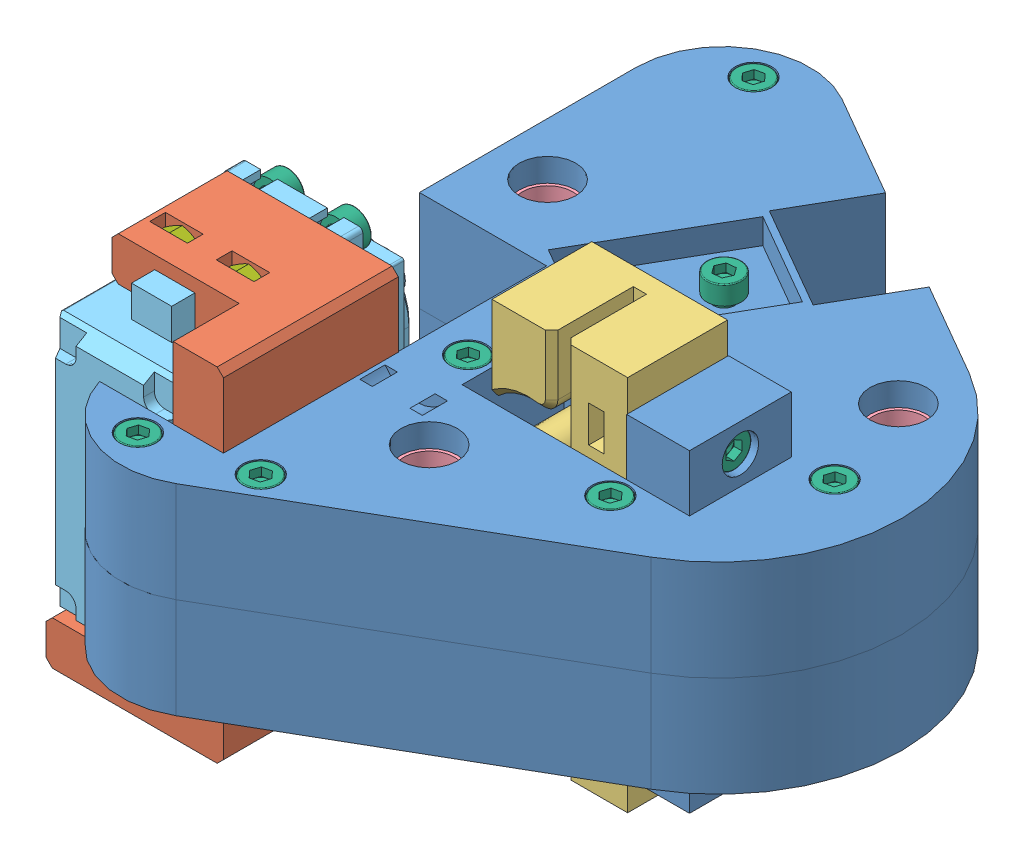
SolidWorks assembly PBewegAssembly, configuration Default. Lengths in mm.
Overall size (91.25 64 109.71).
35 component instances, 7 part files, 82 mates.
Components (placement in the parent):
- PBeweglich-1: PBeweglich [top] at origin size (83.34 25 109.71)
- PServoHolder-1: PServoHolder [Default] at (-25.65 0.0661 17.2) size (34.15 54.65 27.84)
- PRiemenklemme-1: PRiemenklemme [Default] at (7.3 0 3.45) x (1 0 0) z (0 -1 0) size (21.6 15.9 60)
- _LinearBallBearing-1: _LinearBallBearing [Standard] at (29.25 0.4 -15.5) x (1 0 0) z (0 -1 0) size (15 15 24)
- _LinearBallBearing-2: _LinearBallBearing [Standard] at (-29.6 0.4 -18.5) x (1 0 0) z (0 -1 0) size (15 15 24)
- _LinearBallBearing-3: _LinearBallBearing [Standard] at (-2.4435 0.4 27.5) x (1 0 0) z (0 -1 0) size (15 15 24)
- _Analogservo_1501MG-1: _Analogservo_1501MG [Default] at (-35.78 0.0661 45) x (0 -1 0) z (0 0 -1) size (54.65 20.25 44.05)
- PBeweglich-2: PBeweglich [bottom] at origin size (83.34 34 109.71)
- socket head cap screw_iso-2: socket head cap screw_iso [ISO 4762 M3 x 30 - 18N] at (-3 16 -20) x (0 -1 0) z (0.106738 0 0.994287) size (33 5.5 5.5)
- socket head cap screw_iso-4: socket head cap screw_iso [ISO 4762 M3 x 12 - 12N] at (27.1 20.5 8.5) x (-1 0 0) z (0 0 1) size (15 5.5 5.5)
- hex nut style 1 gradeab_iso-1: hex nut style 1 gradeab_iso [ISO - 4032 - M3 - D - N] at (11.9 20.5 8.5) x (0 -0.5 0.866025) z (-1 0 0) size (5.5 6.35 2.4)
- hex nut style 1 gradeab_iso-2: hex nut style 1 gradeab_iso [ISO - 4032 - M3 - D - N] at (14.3 -20.5 8.5) x (0 0.5 -0.866025) z (1 0 0) size (5.5 6.35 2.4)
- socket head cap screw_iso-5: socket head cap screw_iso [ISO 4762 M3 x 12 - 12N] at (27.1 -20.5 8.5) x (-1 0 0) z (0 0.109036 -0.994038) size (15 5.5 5.5)
- socket head cap screw_iso-6: socket head cap screw_iso [ISO 4762 M3 x 30 - 18N] at (19 16 20.1) x (0 -1 0) z (0.214721 0 0.976675) size (33 5.5 5.5)
- socket head cap screw_iso-7: socket head cap screw_iso [ISO 4762 M3 x 30 - 18N] at (-11.75 16 45) x (0 -1 0) z (0.214721 0 0.976675) size (33 5.5 5.5)
- socket head cap screw_iso-8: socket head cap screw_iso [ISO 4762 M3 x 30 - 18N] at (-11.75 16 12) x (0 -1 0) z (0.214721 0 0.976675) size (33 5.5 5.5)
- socket head cap screw_iso-9: socket head cap screw_iso [ISO 4762 M3 x 30 - 18N] at (34.6 16 0) x (0 -1 0) z (0.214721 0 0.976675) size (33 5.5 5.5)
- socket head cap screw_iso-10: socket head cap screw_iso [ISO 4762 M3 x 30 - 18N] at (-27.3127 16 -49) x (0 -1 0) z (0.214721 0 0.976675) size (33 5.5 5.5)
- socket head cap screw_iso-11: socket head cap screw_iso [ISO 4762 M3 x 30 - 18N] at (-27.3127 16 49) x (0 -1 0) z (0.214721 0 0.976675) size (33 5.5 5.5)
- hex nut style 1 gradeab_iso-4: hex nut style 1 gradeab_iso [ISO - 4032 - M3 - D - N] at (-11.75 -13.6 45) x (1 0 0) z (0 1 0) size (5.5 6.35 2.4)
- hex nut style 1 gradeab_iso-5: hex nut style 1 gradeab_iso [ISO - 4032 - M3 - D - N] at (-27.3127 -13.6 49) x (0.866025 0 0.5) z (0 1 0) size (5.5 6.35 2.4)
- hex nut style 1 gradeab_iso-6: hex nut style 1 gradeab_iso [ISO - 4032 - M3 - D - N] at (34.6 -13.6 0) x (1 0 0) z (0 1 0) size (5.5 6.35 2.4)
- hex nut style 1 gradeab_iso-7: hex nut style 1 gradeab_iso [ISO - 4032 - M3 - D - N] at (-27.3127 -13.6 -49) x (1 0 0) z (0 1 0) size (5.5 6.35 2.4)
- hex nut style 1 gradeab_iso-9: hex nut style 1 gradeab_iso [ISO - 4032 - M3 - D - N] at (-3 -13.6 -20) x (1 0 0) z (0 1 0) size (5.5 6.35 2.4)
- hex nut style 1 gradeab_iso-10: hex nut style 1 gradeab_iso [ISO - 4032 - M3 - D - N] at (-11.75 -13.6 12) x (1 0 0) z (0 1 0) size (5.5 6.35 2.4)
- hex nut style 1 gradeab_iso-11: hex nut style 1 gradeab_iso [ISO - 4032 - M3 - D - N] at (19 -13.6 20.1) x (1 0 0) z (0 1 0) size (5.5 6.35 2.4)
- socket head cap screw_iso-14: socket head cap screw_iso [ISO 4762 M3 x 16 - 16N] at (-41.08 24.0711 11.35) x (0 0 1) z (-0.923728 -0.383049 0) size (19 5.5 5.5)
- socket head cap screw_iso-15: socket head cap screw_iso [ISO 4762 M3 x 16 - 16N] at (-30.48 24.0711 11.35) x (0 0 1) z (-0.165915 -0.98614 0) size (19 5.5 5.5)
- socket head cap screw_iso-16: socket head cap screw_iso [ISO 4762 M3 x 16 - 16N] at (-30.48 -23.9389 11.35) x (0 0 1) z (-0.163472 0.986548 0) size (19 5.5 5.5)
- socket head cap screw_iso-17: socket head cap screw_iso [ISO 4762 M3 x 16 - 16N] at (-41.08 -23.9389 11.35) x (0 0 1) z (0.653973 0.756518 0) size (19 5.5 5.5)
- hex nut style 1 gradeab_iso-12: hex nut style 1 gradeab_iso [ISO - 4032 - M3 - D - N] at (-41.08 -23.9389 30.35) size (5.5 6.35 2.4)
- hex nut style 1 gradeab_iso-13: hex nut style 1 gradeab_iso [ISO - 4032 - M3 - D - N] at (-30.48 -23.9389 30.35) x (0.5 0.866025 0) z (0 0 1) size (5.5 6.35 2.4)
- hex nut style 1 gradeab_iso-14: hex nut style 1 gradeab_iso [ISO - 4032 - M3 - D - N] at (-30.58 -24.005 30.35) x (0.5 0.866025 0) z (0 0 1) size (5.5 6.35 2.4)
- hex nut style 1 gradeab_iso-15: hex nut style 1 gradeab_iso [ISO - 4032 - M3 - D - N] at (-30.48 24.0711 30.35) x (0.5 -0.866025 0) z (0 0 1) size (5.5 6.35 2.4)
- hex nut style 1 gradeab_iso-16: hex nut style 1 gradeab_iso [ISO - 4032 - M3 - D - N] at (-41.08 24.0711 30.35) x (-0.5 0.866025 0) z (0 0 1) size (5.5 6.35 2.4)
Mates (geometry in assembly coordinates):
- Coincident3: coincident anti-aligned: plane of PBeweglich-1 through (-11.75 0 16.9) normal (-1 0 0); plane of PServoHolder-1 through (-11.75 0.0661 45.04) normal (1 0 0)
- Concentric3: concentric aligned: cylinder of PBeweglich-1 through (-3 0 -20) axis (0 1 0) radius 1.7; cylinder of socket head cap screw_iso-2 through (-3 47.75 -20) axis (0 1 0) radius 1.5
- Concentric4: concentric aligned: cylinder of PBeweglich-1 through (-38 20.5 8.5) axis (1 0 0) radius 1.75; cylinder of PRiemenklemme-1 through (-3.501 20.5 8.5) axis (1 0 0) radius 1.7
- Concentric6: concentric aligned: cylinder of PBeweglich-1 through (-38 20.5 8.5) axis (1 0 0) radius 1.75; cylinder of socket head cap screw_iso-4 through (58.85 20.5 8.5) axis (1 0 0) radius 1.5
- Coincident8: coincident anti-aligned: plane of PBeweglich-1 through (24.1 20.5 8.5) normal (1 0 0); plane of socket head cap screw_iso-4 through (24.1 17.75 8.5) normal (-1 0 0)
- Coincident13: coincident anti-aligned: plane of PBeweglich-1 through (29.25 12 -15.5) normal (0 -1 0); plane of _LinearBallBearing-1 through (29.25 12 -9) normal (0 1 0)
- Concentric9: concentric anti-aligned: cylinder of PBeweglich-1 through (29.25 12 -15.5) axis (0 -1 0) radius 7.65; cylinder of _LinearBallBearing-1 through (29.25 0.4 -15.5) axis (0 1 0) radius 7.5
- Coincident15: coincident anti-aligned: plane of PBeweglich-1 through (-29.6 12 -18.5) normal (0 -1 0); plane of _LinearBallBearing-2 through (-29.6 12 -12) normal (0 1 0)
- Concentric10: concentric anti-aligned: cylinder of PBeweglich-1 through (-29.6 12 -18.5) axis (0 -1 0) radius 7.65; cylinder of _LinearBallBearing-2 through (-29.6 0.4 -18.5) axis (0 1 0) radius 7.5
- Coincident16: coincident anti-aligned: plane of PBeweglich-1 through (-2.4435 12 27.5) normal (0 -1 0); plane of _LinearBallBearing-3 through (-2.4435 12 34) normal (0 1 0)
- Concentric11: concentric anti-aligned: cylinder of PBeweglich-1 through (-2.4435 12 27.5) axis (0 -1 0) radius 7.65; cylinder of _LinearBallBearing-3 through (-2.4435 0.4 27.5) axis (0 1 0) radius 7.5
- Concentric12: concentric anti-aligned: cylinder of PServoHolder-1 through (-30.48 24.0711 30.35) axis (0 0 -1) radius 1.7; cylinder of _Analogservo_1501MG-1 through (-30.48 24.0711 14.35) axis (0 0 1) radius 2.5
- Concentric13: concentric anti-aligned: cylinder of PServoHolder-1 through (-41.08 24.0711 30.35) axis (0 0 -1) radius 1.7; cylinder of _Analogservo_1501MG-1 through (-41.08 24.0711 14.35) axis (0 0 1) radius 2.5
- Coincident18: coincident anti-aligned: plane of PServoHolder-1 through (-25.65 0.0661 17.2) normal (0 0 -1); plane of _Analogservo_1501MG-1 through (-35.78 0.0661 17.2) normal (0 0 1)
- Concentric15: concentric anti-aligned: cylinder of socket head cap screw_iso-4 through (58.85 20.5 8.5) axis (1 0 0) radius 1.5; cylinder of hex nut style 1 gradeab_iso-1 through (14.3 20.5 8.5) axis (-1 0 0) radius 1.25
- Coincident19: coincident anti-aligned: plane of PRiemenklemme-1 through (14.3 0 16.45) normal (-1 0 0); plane of hex nut style 1 gradeab_iso-1 through (14.3 23.25 10.0877) normal (1 0 0)
- Parallel1: parallel aligned: plane of PRiemenklemme-1 through (7.3 23.4 16.45) normal (0 -1 0); plane of hex nut style 1 gradeab_iso-1 through (14.3 17.75 6.9123) normal (0 -1 0)
- Coincident22: coincident anti-aligned: plane of PRiemenklemme-1 through (14.3 0 16.45) normal (-1 0 0); plane of hex nut style 1 gradeab_iso-2 through (14.3 -17.75 10.0877) normal (1 0 0)
- Concentric18: concentric aligned: cylinder of hex nut style 1 gradeab_iso-2 through (11.9 -20.5 8.5) axis (1 0 0) radius 1.25; cylinder of socket head cap screw_iso-5 through (58.85 -20.5 8.5) axis (1 0 0) radius 1.5
- Parallel2: parallel anti-aligned: plane of PRiemenklemme-1 through (7.3 -23.4 16.45) normal (0 1 0); plane of hex nut style 1 gradeab_iso-2 through (11.9 -23.25 10.0877) normal (0 -1 0)
- Concentric19: concentric aligned: cylinder of socket head cap screw_iso-5 through (58.85 -20.5 8.5) axis (1 0 0) radius 1.5; cylinder of PBeweglich-2 through (-38 -20.5 8.5) axis (1 0 0) radius 1.75
- Coincident24: coincident anti-aligned: plane of socket head cap screw_iso-5 through (24.1 -17.7664 8.7999) normal (-1 0 0); plane of PBeweglich-2 through (24.1 -20.5 8.5) normal (1 0 0)
- Coincident25: coincident anti-aligned: plane of PRiemenklemme-1 through (14.3 0 16.45) normal (-1 0 0); plane of hex nut style 1 gradeab_iso-2 through (14.3 -17.75 10.0877) normal (1 0 0)
- Coincident26: coincident anti-aligned: plane of PBeweglich-1 through (0 0 0) normal (0 -1 0); plane of PBeweglich-2 through (0 0 0) normal (0 1 0)
- Concentric20: concentric anti-aligned: cylinder of PBeweglich-1 through (-11.75 0 45) axis (0 1 0) radius 1.7; cylinder of PBeweglich-2 through (-11.75 0 45) axis (0 -1 0) radius 1.7
- Concentric21: concentric anti-aligned: cylinder of PBeweglich-1 through (-27.3127 0 -49) axis (0 1 0) radius 1.7; cylinder of PBeweglich-2 through (-27.3127 0 -49) axis (0 -1 0) radius 1.7
- Concentric22: concentric aligned: cylinder of PBeweglich-1 through (34.6 0 0) axis (0 1 0) radius 1.7; cylinder of socket head cap screw_iso-9 through (34.6 47.75 0) axis (0 1 0) radius 1.5
- Concentric23: concentric aligned: cylinder of PBeweglich-1 through (19 0 20.1) axis (0 1 0) radius 1.7; cylinder of socket head cap screw_iso-6 through (19 47.75 20.1) axis (0 1 0) radius 1.5
- Coincident27: coincident: circle of PBeweglich-1; cylinder of socket head cap screw_iso-7 through (-11.75 47.75 45) axis (0 1 0) radius 1.5
- Concentric24: concentric aligned: cylinder of PBeweglich-1 through (-11.75 0 12) axis (0 1 0) radius 1.7; cylinder of socket head cap screw_iso-8 through (-11.75 47.75 12) axis (0 1 0) radius 1.5
- Concentric25: concentric aligned: cylinder of PBeweglich-1 through (-27.3127 0 -49) axis (0 1 0) radius 1.7; cylinder of socket head cap screw_iso-10 through (-27.3127 47.75 -49) axis (0 1 0) radius 1.5
- Concentric26: concentric aligned: cylinder of PBeweglich-1 through (-27.3127 0 49) axis (0 1 0) radius 1.7; cylinder of socket head cap screw_iso-11 through (-27.3127 47.75 49) axis (0 1 0) radius 1.5
- Coincident28: coincident anti-aligned: plane of PBeweglich-1 through (34.6 13 0) normal (0 1 0); plane of socket head cap screw_iso-9 through (37.2859 13 -0.5905) normal (0 -1 0)
- Coincident29: coincident anti-aligned: plane of PBeweglich-1 through (-27.3127 13 -49) normal (0 1 0); plane of socket head cap screw_iso-10 through (-24.6269 13 -49.5905) normal (0 -1 0)
- Coincident30: coincident anti-aligned: circle of PBeweglich-1; plane of socket head cap screw_iso-8 through (-9.0641 13 11.4095) normal (0 -1 0)
- Coincident31: coincident anti-aligned: plane of PBeweglich-1 through (19 13 20.1) normal (0 1 0); plane of socket head cap screw_iso-6 through (21.6859 13 19.5095) normal (0 -1 0)
- Coincident32: coincident aligned: plane of PBeweglich-1 through (-11.75 13 45) normal (0 1 0); circle of socket head cap screw_iso-7
- Coincident33: coincident anti-aligned: plane of PBeweglich-1 through (-27.3127 13 49) normal (0 1 0); plane of socket head cap screw_iso-11 through (-24.6269 13 48.4095) normal (0 -1 0)
- Concentric27: concentric anti-aligned: cylinder of socket head cap screw_iso-7 through (-11.75 47.75 45) axis (0 1 0) radius 1.5; circle of hex nut style 1 gradeab_iso-4
- Concentric29: concentric aligned: cylinder of socket head cap screw_iso-11 through (-27.3127 47.75 49) axis (0 1 0) radius 1.5; cylinder of hex nut style 1 gradeab_iso-5 through (-27.3127 -16 49) axis (0 1 0) radius 1.25
- Coincident34: coincident aligned: cylinder of socket head cap screw_iso-6 through (19 47.75 20.1) axis (0 1 0) radius 1.5; circle of hex nut style 1 gradeab_iso-11
- Concentric30: concentric aligned: cylinder of socket head cap screw_iso-8 through (-11.75 47.75 12) axis (0 1 0) radius 1.5; cylinder of hex nut style 1 gradeab_iso-10 through (-11.75 -16 12) axis (0 1 0) radius 1.25
- Concentric31: concentric aligned: cylinder of socket head cap screw_iso-2 through (-3 47.75 -20) axis (0 1 0) radius 1.5; cylinder of hex nut style 1 gradeab_iso-9 through (-3 -16 -20) axis (0 1 0) radius 1.25
- Concentric32: concentric aligned: cylinder of socket head cap screw_iso-10 through (-27.3127 47.75 -49) axis (0 1 0) radius 1.5; cylinder of hex nut style 1 gradeab_iso-7 through (-27.3127 -16 -49) axis (0 1 0) radius 1.25
- Concentric33: concentric aligned: cylinder of socket head cap screw_iso-9 through (34.6 47.75 0) axis (0 1 0) radius 1.5; cylinder of hex nut style 1 gradeab_iso-6 through (34.6 -16 0) axis (0 1 0) radius 1.25
- Parallel3: parallel: line of PBeweglich-2 through (22 -16 21.8321) axis (0 0 -1); plane of hex nut style 1 gradeab_iso-11 through (21.75 -16 18.5123) normal (1 0 0)
- Parallel4: parallel: line of PBeweglich-2 through (-8.75 -16 46.7321) axis (0 0 -1); plane of hex nut style 1 gradeab_iso-4 through (-9 -16 43.4123) normal (1 0 0)
- Parallel5: parallel: line of PBeweglich-2 through (-25.5807 -16 52) axis (0.5 0 -0.866025); plane of hex nut style 1 gradeab_iso-5 through (-24.1373 -16 49) normal (0.866025 0 0.5)
- Parallel6: parallel: line of PBeweglich-2 through (-8.75 -16 13.7321) axis (0 0 -1); plane of hex nut style 1 gradeab_iso-10 through (-9 -16 10.4123) normal (1 0 0)
- Parallel7: parallel: line of PBeweglich-2 through (0 -16 -18.2679) axis (0 0 -1); plane of hex nut style 1 gradeab_iso-9 through (-0.25 -16 -21.5877) normal (1 0 0)
- Parallel8: parallel: line of PBeweglich-2 through (37.6 -16 1.7321) axis (0 0 -1); plane of hex nut style 1 gradeab_iso-6 through (37.35 -16 -1.5877) normal (1 0 0)
- Parallel9: parallel: line of PBeweglich-2 through (-24.3127 -16 -47.2679) axis (0 0 -1); plane of hex nut style 1 gradeab_iso-7 through (-24.5627 -16 -50.5877) normal (1 0 0)
- Coincident43: coincident anti-aligned: plane of PBeweglich-2 through (0 -13.6 0) normal (0 -1 0); plane of hex nut style 1 gradeab_iso-11 through (19 -13.6 16.9246) normal (0 1 0)
- Coincident44: coincident anti-aligned: plane of PBeweglich-2 through (0 -13.6 0) normal (0 -1 0); plane of hex nut style 1 gradeab_iso-10 through (-11.75 -13.6 8.8246) normal (0 1 0)
- Coincident45: coincident anti-aligned: plane of PBeweglich-2 through (0 -13.6 0) normal (0 -1 0); plane of hex nut style 1 gradeab_iso-6 through (34.6 -13.6 -3.1754) normal (0 1 0)
- Coincident46: coincident anti-aligned: plane of PBeweglich-2 through (0 -13.6 0) normal (0 -1 0); plane of hex nut style 1 gradeab_iso-9 through (-3 -13.6 -23.1754) normal (0 1 0)
- Coincident47: coincident anti-aligned: plane of PBeweglich-2 through (0 -13.6 0) normal (0 -1 0); plane of hex nut style 1 gradeab_iso-7 through (-27.3127 -13.6 -52.1754) normal (0 1 0)
- Coincident48: coincident anti-aligned: plane of PBeweglich-2 through (0 -13.6 0) normal (0 -1 0); plane of hex nut style 1 gradeab_iso-4 through (-11.75 -13.6 41.8246) normal (0 1 0)
- Coincident49: coincident anti-aligned: plane of PBeweglich-2 through (0 -13.6 0) normal (0 -1 0); plane of hex nut style 1 gradeab_iso-5 through (-25.725 -13.6 46.25) normal (0 1 0)
- Coincident52: coincident anti-aligned: plane of _Analogservo_1501MG-1 through (-35.78 0.0661 45) normal (0 0 1); plane of PBeweglich-2 through (0 -12 45) normal (0 0 -1)
- Concentric39: concentric aligned: cylinder of PServoHolder-1 through (-41.08 24.0711 30.35) axis (0 0 -1) radius 1.7; cylinder of socket head cap screw_iso-14 through (-41.08 24.0711 -20.4) axis (0 0 -1) radius 1.5
- Coincident55: coincident anti-aligned: plane of _Analogservo_1501MG-1 through (-35.78 0.0661 14.35) normal (0 0 -1); plane of socket head cap screw_iso-14 through (-42.1334 26.6114 14.35) normal (0 0 1)
- Concentric40: concentric aligned: cylinder of PServoHolder-1 through (-30.48 24.0711 30.35) axis (0 0 -1) radius 1.7; cylinder of socket head cap screw_iso-15 through (-30.48 24.0711 -20.4) axis (0 0 -1) radius 1.5
- Coincident56: coincident aligned: plane of _Analogservo_1501MG-1 through (-35.78 0.0661 14.35) normal (0 0 -1); circle of socket head cap screw_iso-15
- Concentric41: concentric aligned: cylinder of PServoHolder-1 through (-30.48 -23.9389 30.35) axis (0 0 -1) radius 1.7; cylinder of socket head cap screw_iso-16 through (-30.48 -23.9389 -20.4) axis (0 0 -1) radius 1.5
- Concentric42: concentric aligned: cylinder of PServoHolder-1 through (-41.08 -23.9389 30.35) axis (0 0 -1) radius 1.7; cylinder of socket head cap screw_iso-17 through (-41.08 -23.9389 -20.4) axis (0 0 -1) radius 1.5
- Coincident57: coincident anti-aligned: plane of _Analogservo_1501MG-1 through (-35.78 0.0661 14.35) normal (0 0 -1); plane of socket head cap screw_iso-17 through (-38.9996 -25.7373 14.35) normal (0 0 1)
- Coincident58: coincident anti-aligned: plane of _Analogservo_1501MG-1 through (-35.78 0.0661 14.35) normal (0 0 -1); plane of socket head cap screw_iso-16 through (-27.767 -23.4894 14.35) normal (0 0 1)
- Concentric43: concentric anti-aligned: cylinder of socket head cap screw_iso-17 through (-41.08 -23.9389 -20.4) axis (0 0 -1) radius 1.5; cylinder of hex nut style 1 gradeab_iso-12 through (-41.08 -23.9389 27.95) axis (0 0 1) radius 1.25
- Parallel12: parallel anti-aligned: plane of PServoHolder-1 through (-38.08 -21.2589 27.85) normal (-1 0 0); plane of hex nut style 1 gradeab_iso-12 through (-38.33 -22.3512 27.95) normal (1 0 0)
- Coincident60: coincident anti-aligned: plane of PServoHolder-1 through (-41.08 -23.9389 30.35) normal (0 0 -1); plane of hex nut style 1 gradeab_iso-12 through (-41.08 -20.7635 30.35) normal (0 0 1)
- Concentric44: concentric anti-aligned: cylinder of socket head cap screw_iso-16 through (-30.48 -23.9389 -20.4) axis (0 0 -1) radius 1.5; cylinder of hex nut style 1 gradeab_iso-13 through (-30.48 -23.9389 27.95) axis (0 0 1) radius 1.25
- Parallel13: parallel anti-aligned: plane of PServoHolder-1 through (-27.48 -21.2589 27.85) normal (-1 0 0); plane of hex nut style 1 gradeab_iso-13 through (-27.73 -25.5266 27.95) normal (1 0 0)
- Coincident62: coincident anti-aligned: plane of PServoHolder-1 through (-30.48 -23.9389 30.35) normal (0 0 -1); plane of hex nut style 1 gradeab_iso-13 through (-33.23 -22.3512 30.35) normal (0 0 1)
- Coincident63: coincident anti-aligned: cylinder of socket head cap screw_iso-14 through (-41.08 24.0711 -20.4) axis (0 0 -1) radius 1.5; circle of hex nut style 1 gradeab_iso-16
- Concentric45: concentric aligned: cylinder of socket head cap screw_iso-15 through (-30.48 24.0711 -20.4) axis (0 0 -1) radius 1.5; circle of hex nut style 1 gradeab_iso-15
- Coincident64: coincident anti-aligned: plane of PServoHolder-1 through (-30.48 24.0711 30.35) normal (0 0 -1); plane of hex nut style 1 gradeab_iso-15 through (-27.73 25.6588 30.35) normal (0 0 1)
- Coincident65: coincident anti-aligned: plane of PServoHolder-1 through (-41.08 24.0711 30.35) normal (0 0 -1); plane of hex nut style 1 gradeab_iso-16 through (-43.83 22.4834 30.35) normal (0 0 1)
- Parallel14: parallel anti-aligned: plane of PServoHolder-1 through (-44.08 21.3911 27.85) normal (1 0 0); plane of hex nut style 1 gradeab_iso-16 through (-43.83 25.6588 27.95) normal (-1 0 0)
- Parallel15: parallel aligned: plane of PServoHolder-1 through (-33.48 21.3911 27.85) normal (1 0 0); plane of hex nut style 1 gradeab_iso-15 through (-27.73 22.4834 27.95) normal (1 0 0)
- Coincident66: coincident anti-aligned: plane of PBeweglich-1 through (18.1 25 -41) normal (-1 0 0); plane of PRiemenklemme-1 through (18.1 0 0.55) normal (1 0 0)
- Concentric46: concentric aligned: circle of PRiemenklemme-1; cylinder of socket head cap screw_iso-5 through (58.85 -20.5 8.5) axis (1 0 0) radius 1.5
